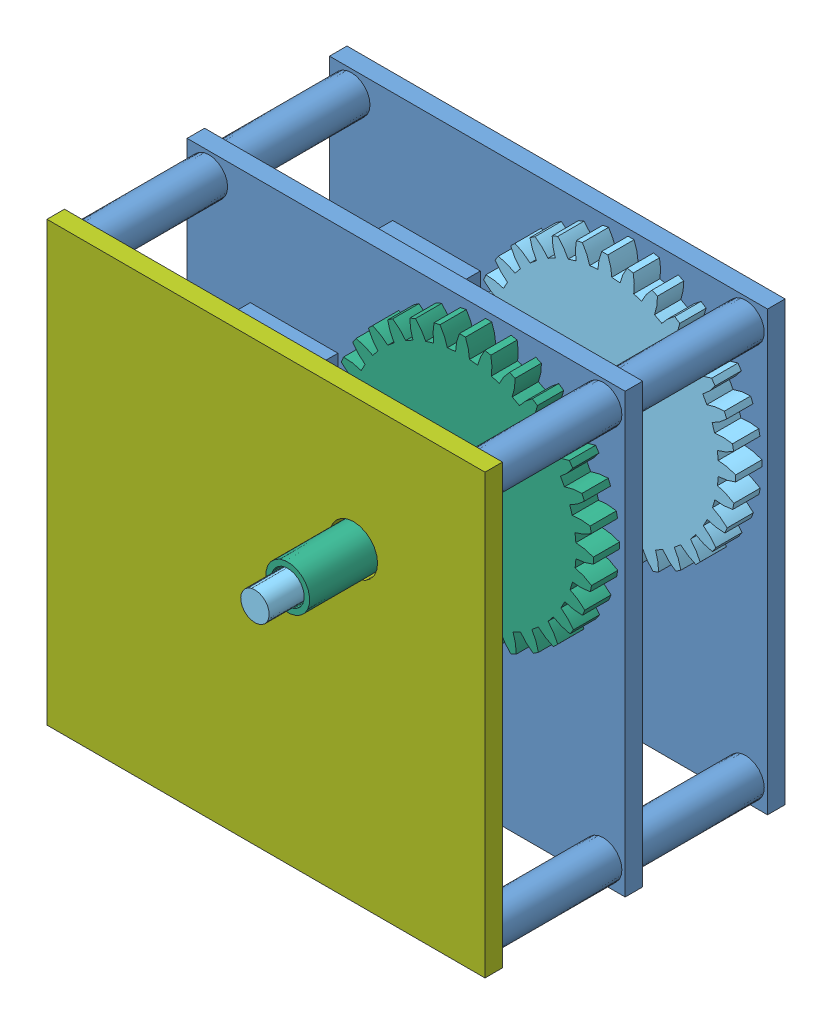
SolidWorks assembly Gearbox, configuration Default. Lengths in mm.
Overall size (108.51 108.51 110).
13 component instances, 8 part files, 29 mates.
Components (placement in the parent):
- Base Plate-1: Base Plate [Default] at (38.4043 79.6142 96.8195) size (100 100 34)
- Reference - Motor-1: Reference - Motor [Default] at (18.7926 51.7502 77.8195) size (42 31 29)
- Gear 32-1: Gear 32 [Metric - Spur gear 1.75M 32T 14.5PA 6FW ---S32N75H50L0.8N] at (18.7926 59.7502 107.8195) x (0 0 -1) z (1 0 0) size (9.25 59.33 59.33)
- Reference - Sensor-1: Reference - Sensor [Default] at (14.0832 99.3452 108.8195) x (1 0 0) z (0 -1 0) size (34.5 11.5 15)
- Gear 32 - Inner-1: Gear 32 - Inner [Metric - Spur gear 1.75M 32T 14.5PA 6FW ---S32N75H50L0.8N] at (58.3876 99.3452 107.8195) x (0 0 -1) z (0.9583 -0.285764 0) size (96 59.33 59.33)
- Base Plate-2: Base Plate [Default] at (38.4043 79.6142 129.3195) size (100 100 34)
- Gear 32-3: Gear 32 [Metric - Spur gear 1.75M 32T 14.5PA 6FW ---S32N75H50L0.8N] at (18.7926 59.7502 140.3195) x (0 0 -1) z (0.996607 -0.082304 0) size (9.25 59.33 59.33)
- Reference - Motor-2: Reference - Motor [Default] at (18.7926 51.7502 110.3195) size (42 31 29)
- Reference - Sensor-2: Reference - Sensor [Default] at (14.0832 99.3452 141.3195) x (1 0 0) z (0 -1 0) size (34.5 11.5 15)
- Gear 32 - Outter-1: Gear 32 - Outter [Metric - Spur gear 1.75M 32T 14.5PA 6FW ---S32N75H50L0.8N] at (58.3876 99.3452 140.3195) x (0 0 -1) z (0.994731 0.102516 0) size (60 59.33 59.33)
- Top Plate-1: Top Plate [Default] at (38.4043 79.6142 161.3195) size (100 100 4)
- Reference - Magnet-1: Reference - Magnet [Default] at (33.9876 99.3452 140.3195) x (-0.681934 -0.731414 0) z (0.731414 -0.681934 0) size (3 2.5 3)
- Reference - Magnet-2: Reference - Magnet [Default] at (33.9876 99.3452 105.3195) x (1 0 0) z (0 -1 0) size (3 2.5 3)
Mates (geometry in assembly coordinates):
- Coincident1: coincident anti-aligned: plane of Base Plate-1 through (38.4043 79.6142 96.8195) normal (0 0 -1); plane of Reference - Motor-1 through (18.7926 51.7502 96.8195) normal (0 0 1)
- Distance2: distance = 1 mm anti-aligned: plane of Gear 32-1 through (18.7926 59.7502 101.8195) normal (0 0 -1); plane of Base Plate-1 through (38.4043 79.6142 100.8195) normal (0 0 1)
- Distance3: distance = 1 mm: plane of ? through (57.6971 98.7918 101.8195) normal (0 0 -1); plane of Base Plate-1 through (38.4043 79.6142 100.8195) normal (0 0 1)
- Distance4: distance = 1 mm anti-aligned: plane of Reference - Sensor-1 through (14.0832 99.3452 108.8195) normal (0 0 -1); plane of Gear 32-1 through (18.7926 59.7502 107.8195) normal (0 0 1)
- Coincident6: coincident: point of ?
- Concentric1: concentric aligned: circle of Reference - Motor-1; circle of Gear 32-1
- Distance5: distance = 1 mm anti-aligned: plane of Gear 32 - Inner-1 through (58.3876 99.3452 101.8195) normal (0 0 -1); plane of Base Plate-1 through (38.4043 79.6142 100.8195) normal (0 0 1)
- Coincident21: coincident: point of Gear 32 - Inner-1; line of assembly
- Concentric3: concentric aligned: circle of Base Plate-1; circle of Reference - Sensor-1
- Parallel1: parallel aligned: line of Base Plate-1 through (2.8332 104.3452 108.8195) axis (0 -1 0); line of Reference - Sensor-1 through (-3.1668 106.8452 110.8195) axis (0 -1 0)
- Coincident24: coincident anti-aligned: plane of Base Plate-2 through (38.4043 79.6142 129.3195) normal (0 0 -1); plane of Reference - Motor-2 through (18.7926 51.7502 129.3195) normal (0 0 1)
- Concentric4: concentric anti-aligned: circle of Base Plate-2; circle of Reference - Motor-2
- Distance6: distance = 1 mm anti-aligned: plane of Base Plate-2 through (38.4043 79.6142 133.3195) normal (0 0 1); plane of Gear 32-3 through (18.7926 59.7502 134.3195) normal (0 0 -1)
- Concentric5: concentric anti-aligned: circle of Base Plate-2; circle of Gear 32-3
- Coincident27: coincident anti-aligned: plane of Base Plate-2 through (38.4043 79.6142 141.3195) normal (0 0 1); plane of Reference - Sensor-2 through (14.0832 99.3452 141.3195) normal (0 0 -1)
- Concentric7: concentric aligned: circle of Base Plate-2; circle of Reference - Sensor-2
- Concentric8: concentric anti-aligned: circle of Base Plate-1; circle of Base Plate-2
- Coincident30: coincident anti-aligned: plane of Base Plate-1 through (83.4043 124.6142 130.8195) normal (0 0 1); plane of Base Plate-2 through (83.4043 124.6142 130.8195) normal (0 0 -1)
- Concentric9: concentric anti-aligned: circle of Base Plate-1; circle of Base Plate-2
- Distance7: distance = 1 mm anti-aligned: plane of Gear 32 - Outter-1 through (58.3876 99.3452 134.3195) normal (0 0 -1); plane of Base Plate-2 through (38.4043 79.6142 133.3195) normal (0 0 1)
- Concentric10: concentric anti-aligned: circle of Base Plate-2; circle of Gear 32 - Outter-1
- Concentric11: concentric anti-aligned: circle of Base Plate-2; circle of Reference - Motor-2
- Concentric12: concentric anti-aligned: circle of Base Plate-2; circle of Top Plate-1
- Concentric13: concentric anti-aligned: circle of Base Plate-2; circle of Top Plate-1
- Coincident33: coincident anti-aligned: plane of Base Plate-2 through (-6.5957 34.6142 163.3195) normal (0 0 1); plane of Top Plate-1 through (-6.5957 34.6142 163.3195) normal (0 0 -1)
- Concentric14: concentric aligned: circle of Gear 32 - Inner-1; circle of Reference - Magnet-2
- Coincident36: coincident anti-aligned: plane of Gear 32 - Inner-1 through (33.9876 99.3452 105.3195) normal (0 0 1); plane of Reference - Magnet-2 through (33.9876 99.3452 105.3195) normal (0 0 -1)
- Concentric17: concentric anti-aligned: circle of Gear 32 - Outter-1; circle of Reference - Magnet-1
- Coincident37: coincident anti-aligned: plane of Gear 32 - Outter-1 through (33.9876 99.3452 137.8195) normal (0 0 1); plane of Reference - Magnet-1 through (33.9876 99.3452 137.8195) normal (0 0 -1)
